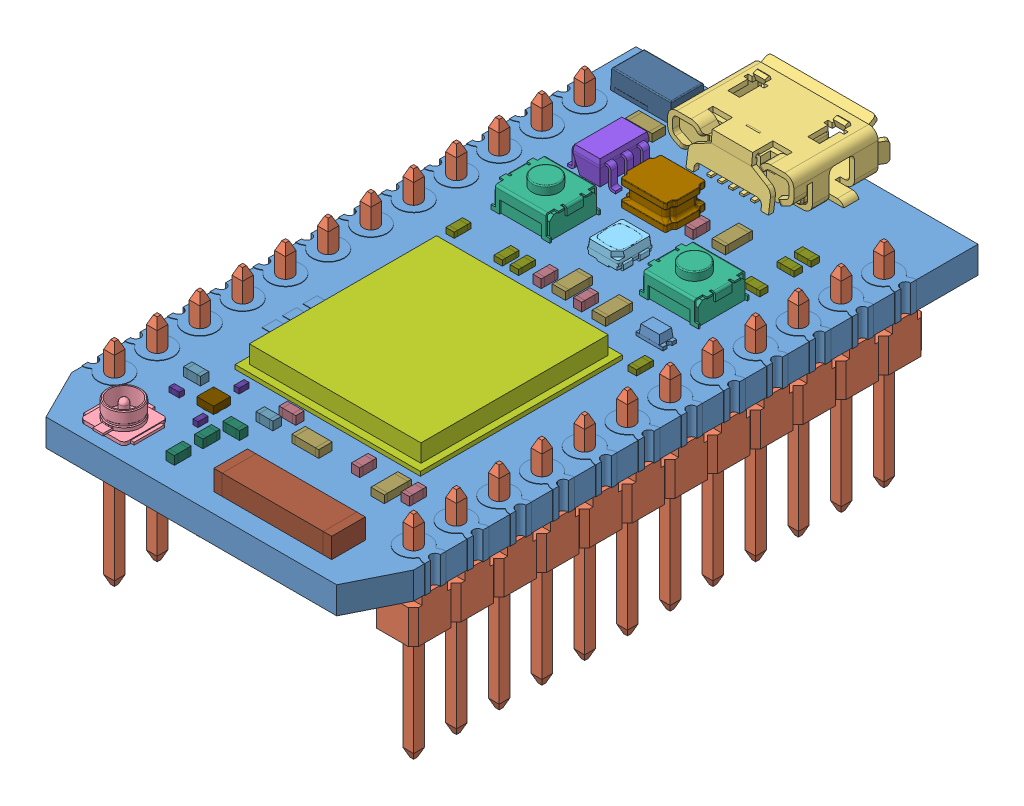
SolidWorks assembly 13774, configuration Default. Lengths in mm.
Overall size (20.37 13.61 37.65).
43 component instances, 19 part files, 0 mates.
Components (placement in the parent):
- Board-1: Board [Default] at (-59.1192 19.9977 0) x (1 0 0) z (0 1 0) size (20.37 36.58 1.65)
- 961102-6804-XX-1: 961102-6804-XX [Default] at (-59.0992 17.8975 -3.048) x (0 0 -1) z (0 -1 0) size (30.48 2.5 12.6)
- 961102-6804-XX-2: 961102-6804-XX [Default] at (-41.3192 17.8975 -3.048) x (0 0 -1) z (0 -1 0) size (30.48 2.5 12.6)
- 475890001-1: 475890001 [Default] at (-48.9592 22.1477 -23.548) x (-1 0 0) z (0 0 1) size (8.65 3.31 5.89)
- RECE.20279-1: RECE.20279 [Default] at (-55.0252 19.9977 -2.062) x (0 0 1) z (-1 0 0) size (3.1 1.25 3)
- CLVBA-FKA-1: CLVBA-FKA [Default] at (-48.9292 20.4327 -25.416) size (2 0.9 2.02)
- SMDButton-1: SMDButton [Default] at (-53.3032 19.9977 -25.4) size (3.5 1.9 3)
- SMDButton-2: SMDButton [Default] at (-44.4767 19.9977 -25.4) size (3.5 1.9 3)
- PhotonChip-1: PhotonChip [Default] at (-48.9202 19.9977 -14.066) x (-1 0 0) z (0 0 -1) size (11 1.3 12)
- IC-1: IC [Default] at (-53.5692 19.9977 -28.088) x (-1 0 0) z (0 0 -1) size (2.84 1.6 2.9)
- Box-1: Box [Default] at (-49.9992 20.7477 -29.067) x (0 0 1) z (-1 0 0) size (2.4 1.5 3)
- 33m52-1: 33m52 [Default] at (-55.8492 19.9977 -34.5915) x (1 0 0) z (0 0 -1) size (4 1.15 2)
- Antenna-1: Antenna [Default] at (-45.2687 19.9977 -2.143) size (7 1.2 2)
- ob1-1: ob1 [Default] at (-48.1592 19.9977 -6.369) size (1.6 0.45 0.8)
- ob1-2: ob1 [Default] at (-43.4792 19.9977 -6.388) x (0 0 1) z (-1 0 0) size (1.6 0.45 0.8)
- ob1-3: ob1 [Default] at (-54.5092 19.9977 -32.531) size (1.6 0.45 0.8)
- ob1-4: ob1 [Default] at (-46.1462 19.9977 -29.3115) x (0 0 1) z (-1 0 0) size (1.6 0.45 0.8)
- ob1-5: ob1 [Default] at (-46.0192 19.9977 -22.0775) x (0 0 1) z (-1 0 0) size (1.6 0.45 0.8)
- ob1-6: ob1 [Default] at (-48.5592 19.9977 -22.2312) x (0 0 1) z (-1 0 0) size (1.6 0.45 0.8)
- ob1_ob2-1: ob1_ob2 [Default] at (-42.4456 19.9977 -6.6976) x (0 0 -1) z (1 0 0) size (1 0.5 0.5)
- ob1_ob2purp-1: ob1_ob2purp [Default] at (-50.6374 19.9977 -6.2698) size (1 0.5 0.5)
- ob1_ob2-2: ob1_ob2 [Default] at (-45.4072 19.9977 -6.6976) x (0 0 -1) z (1 0 0) size (1 0.5 0.5)
- ob1_ob2-3: ob1_ob2 [Default] at (-50.2372 19.9977 -7.235) size (1 0.5 0.5)
- ob1_ob2-4: ob1_ob2 [Default] at (-49.7338 19.9977 -21.8106) x (0 0 -1) z (1 0 0) size (1 0.5 0.5)
- ob1_ob2-5: ob1_ob2 [Default] at (-47.3297 19.9977 -21.8106) x (0 0 -1) z (1 0 0) size (1 0.5 0.5)
- ob1_ob2-6: ob1_ob2 [Default] at (-47.7383 19.9977 -28.8464) x (0 0 -1) z (1 0 0) size (1 0.5 0.5)
- ob1_ob2purp-2: ob1_ob2purp [Default] at (-55.097 19.9977 -6.4222) size (1 0.5 0.5)
- ob1_ob2white-1: ob1_ob2white [Default] at (-51.1262 19.9977 -4.7839) size (1 0.5 0.5)
- ob1_ob2white-2: ob1_ob2white [Default] at (-51.5411 19.9977 -3.5226) x (0 0 1) z (-1 0 0) size (1 0.5 0.5)
- ob1_ob2white-3: ob1_ob2white [Default] at (-51.5396 19.9977 -1.8228) x (0 0 1) z (-1 0 0) size (1 0.5 0.5)
- smddiode_ob2-1: smddiode_ob2 [Default] at (-43.0619 19.9977 -30.6725) size (1 0.32 0.5)
- smddiode_ob2-2: smddiode_ob2 [Default] at (-43.0619 19.9977 -29.6547) size (1 0.32 0.5)
- smddiode_ob2-3: smddiode_ob2 [Default] at (-43.0619 19.9977 -27.625) size (1 0.32 0.5)
- smddiode_ob2-4: smddiode_ob2 [Default] at (-54.9362 19.9977 -31.365) size (1 0.32 0.5)
- smddiode_ob2-5: smddiode_ob2 [Default] at (-54.9046 19.9977 -21.8106) x (0 0 -1) z (1 0 0) size (1 0.32 0.5)
- smddiode_ob2-6: smddiode_ob2 [Default] at (-52.0446 19.9977 -21.8106) x (0 0 -1) z (1 0 0) size (1 0.32 0.5)
- smddiode_ob2-7: smddiode_ob2 [Default] at (-51.0748 19.9977 -21.8106) x (0 0 -1) z (1 0 0) size (1 0.32 0.5)
- smddiode_ob2-8: smddiode_ob2 [Default] at (-42.4043 19.9977 -20.1469) x (0 0 -1) z (1 0 0) size (1 0.32 0.5)
- ob1_ob3-1: ob1_ob3 [Default] at (-54.9083 20.1477 -4.9292) x (1 0 0) z (0 1 0) size (0.6 0.3 0.3)
- ob1_ob3-2: ob1_ob3 [Default] at (-52.5299 20.1477 -4.2624) x (0 0 -1) z (0 1 0) size (0.6 0.3 0.3)
- ob1_ob3-3: ob1_ob3 [Default] at (-53.0359 20.1477 -7.2088) x (0 0 -1) z (0 1 0) size (0.6 0.3 0.3)
- IC2-1: IC2 [Default] at (-53.2165 20.0177 -5.58) size (1 0.45 1)
- singleled-1: singleled [Default] at (-43.4602 20.1977 -22.117) size (1.6 0.7 0.8)
